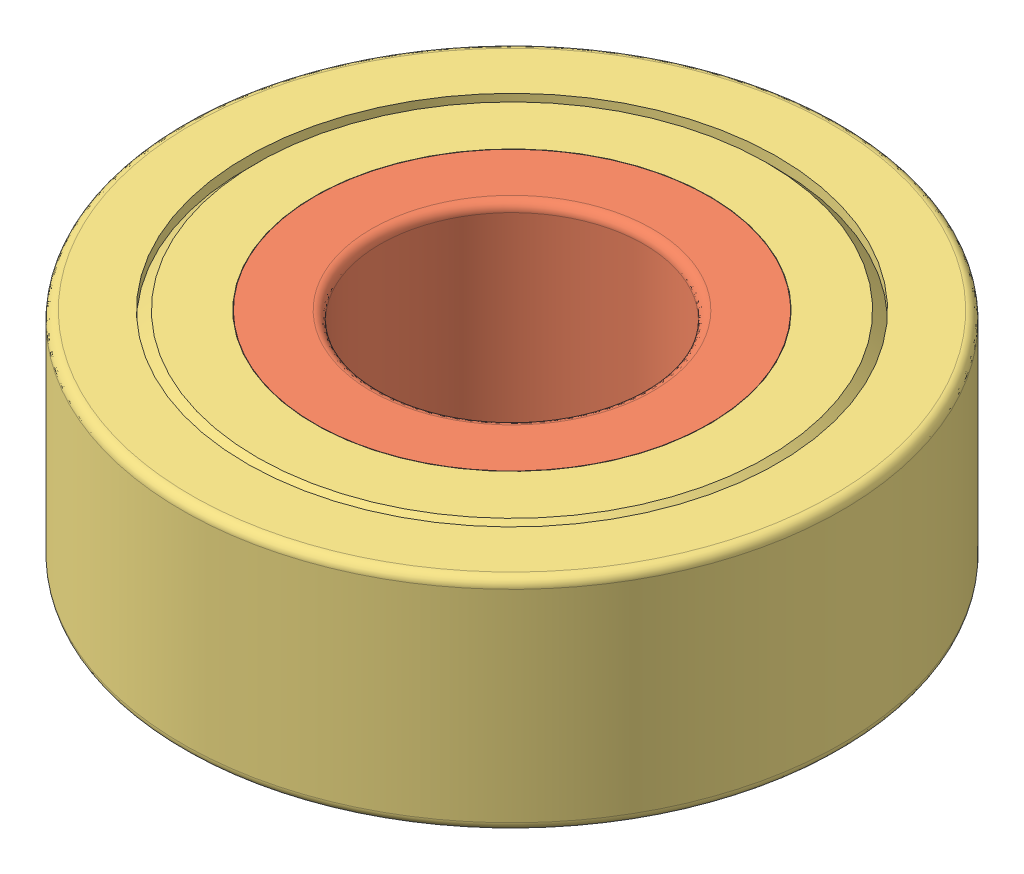
SolidWorks assembly 696ZZ Bearing, configuration Default. Lengths in mm.
Overall size (15.58 5 15.58).
12 component instances, 3 part files, 12 mates.
Components (placement in the parent):
- ball bearing-3: ball bearing [Default] at (-8.9619 -2.7293 0.1818) x (0.444401 0.889708 -0.104533) z (0.713997 -0.281306 0.641152) size (2.7 2.7 2.7)
- ball bearing-2: ball bearing [Default] at (-2.8221 2.4974 -4.5597) x (0.068858 0.146635 0.986791) z (-0.685148 -0.712022 0.153614) size (2.7 2.7 2.7)
- ball bearing-1: ball bearing [Default] at (-3.7028 5.9901 -3.9309) x (0.28408 -0.958228 -0.033144) z (-0.506929 -0.179448 0.843102) size (2.7 2.7 2.7)
- ball bearing-10: ball bearing [Default] at (-0.4124 2.7884 -8.0398) x (0.998941 0.024755 -0.038778) z (0.039629 -0.034863 0.998606) size (2.7 2.7 2.7)
- ball bearing-8: ball bearing [Default] at (-3.307 1.4171 -7.6483) x (0.897908 0.343444 -0.27533) z (0.405535 -0.402192 0.820843) size (2.7 2.7 2.7)
- ball bearing-7: ball bearing [Default] at (-7.5678 4.9126 -7.8607) x (0.925697 -0.372266 -0.067103) z (-0.05952 -0.318536 0.94604) size (2.7 2.7 2.7)
- ball bearing-6: ball bearing [Default] at (0.3979 3.4094 -4.0154) x (0.993103 -0.041629 -0.109611) z (0.094371 -0.270991 0.957945) size (2.7 2.7 2.7)
- ball bearing-9: ball bearing [Default] at (-6.0376 3.6584 -8.4022) x (0.983933 -0.065456 -0.166108) z (0.104106 -0.545494 0.831624) size (2.7 2.7 2.7)
- ball bearing-4: ball bearing [Default] at (-2.7537 -0.7778 -2.9999) x (0.769778 0.563696 0.29948) z (-0.478994 0.20001 0.854728) size (2.7 2.7 2.7)
- ball bearing-5: ball bearing [Default] at (-1.2092 -1.699 -1.9935) x (0.661202 0.749392 -0.034976) z (0.073954 -0.018714 0.997086) size (2.7 2.7 2.7)
- 696ZZ Inner Bearing Race-1: 696ZZ Inner Bearing Race [Default] at (0.108 2.8577 -4.1547) size (9.15 5 9.15)
- 696ZZ Outer Bearing Race-1: 696ZZ Outer Bearing Race [Default] at (0.108 2.8577 -4.1547) x (0.999209 0 0.039778) z (-0.039778 0 0.999209) size (15 5 15)
Mates (geometry in assembly coordinates):
- Tangent1: tangent anti-aligned: sphere of ball bearing-2; torus of 696ZZ Inner Bearing Race-1
- Tangent3: tangent anti-aligned: sphere of ball bearing-4; torus of 696ZZ Inner Bearing Race-1
- Tangent4: tangent anti-aligned: sphere of ball bearing-5; torus of 696ZZ Inner Bearing Race-1
- Tangent6: tangent anti-aligned: sphere of ball bearing-3; torus of 696ZZ Inner Bearing Race-1
- Tangent7: tangent anti-aligned: sphere of ball bearing-1; torus of 696ZZ Inner Bearing Race-1
- Tangent12: tangent anti-aligned: sphere of ball bearing-8; torus of 696ZZ Inner Bearing Race-1
- Tangent15: tangent anti-aligned: sphere of ball bearing-7; torus of 696ZZ Inner Bearing Race-1
- Tangent16: tangent anti-aligned: sphere of ball bearing-9; torus of 696ZZ Inner Bearing Race-1
- Tangent17: tangent anti-aligned: sphere of ball bearing-10; torus of 696ZZ Inner Bearing Race-1
- Tangent18: tangent anti-aligned: sphere of ball bearing-6; torus of 696ZZ Inner Bearing Race-1
- Concentric2: concentric aligned: cylinder of 696ZZ Inner Bearing Race-1 through (0.108 -2.1458 -4.1547) axis (0 1 0) radius 4.4835; cylinder of 696ZZ Outer Bearing Race-1 through (0.108 -2.1435 -4.1547) axis (0 1 0) radius 4.4935
- Coincident2: coincident aligned: plane of 696ZZ Inner Bearing Race-1 through (3.308 2.8577 -4.1547) normal (0 1 0); plane of 696ZZ Outer Bearing Race-1 through (6.1467 2.8577 -3.9143) normal (0 1 0)
